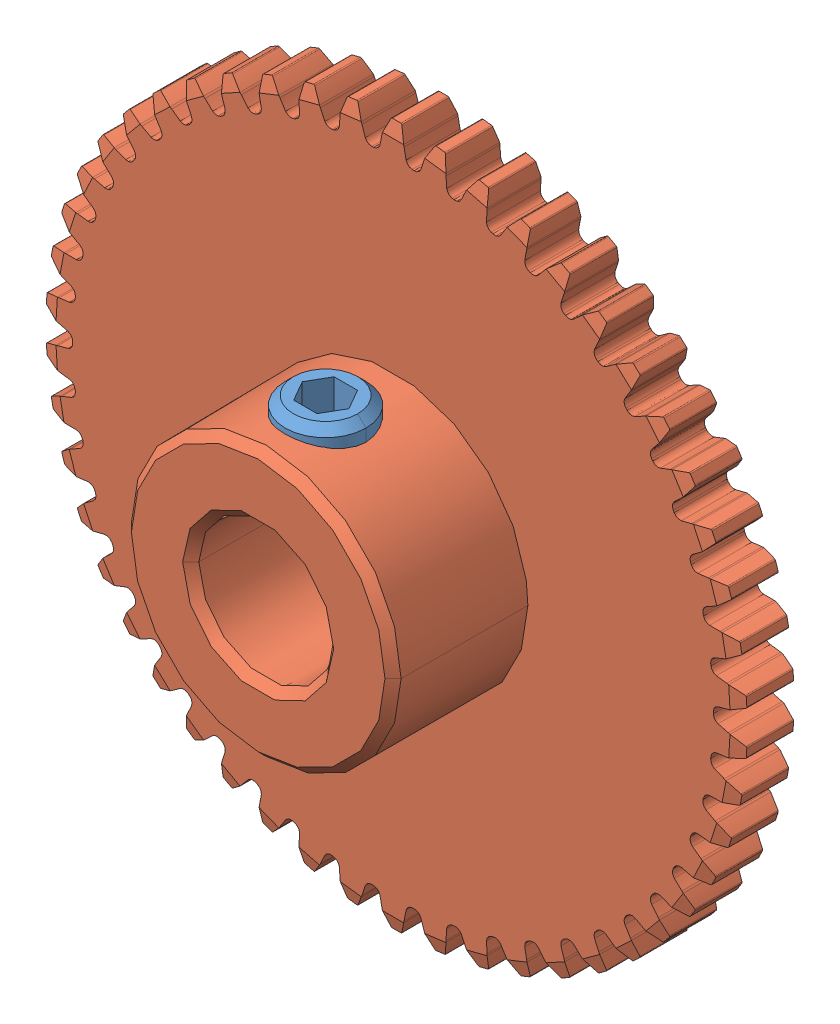
SolidWorks assembly StepperGear, configuration Default. Lengths in mm.
Overall size (25.97 26 7).
2 component instances, 2 part files, 0 mates.
Components (placement in the parent):
- GEABB0_5_50_2_B_5_3-1: GEABB0_5_50_2_B_5_3 [Default] at (0 2.5 4.5) x (0 -1 0) z (-1 0 0) size (3 3 3)
- GEABB0_5_50_2_B_5_5-1: GEABB0_5_50_2_B_5_5 [Default] at origin size (25.97 26 7)
